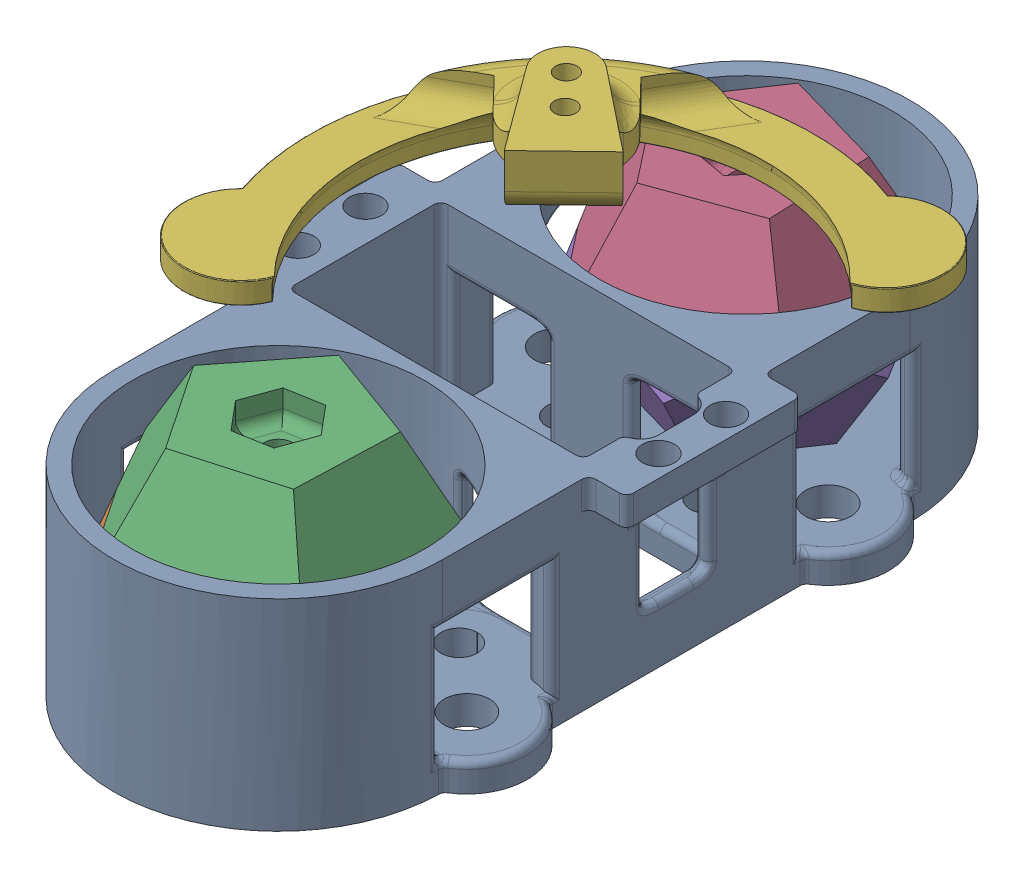
SolidWorks assembly MS25_Marker_DropperAssembly, configuration Default. Lengths in mm.
Overall size (83.01 48 114.65).
6 component instances, 4 part files, 7 mates.
Components (placement in the parent):
- MS25_Marker_DropperBody-1: MS25_Marker_DropperBody [Default] at (-21.4073 8.5238 12.4012) size (56.8 28.3 111.9)
- MS25_Marker_DodecBoltSide-1: MS25_Marker_DodecBoltSide [Default] at (-21.4073 -11.7762 45.2512) x (-0.96134 0 0.275365) z (-0.275365 0 -0.96134) size (36.8 15 36.85)
- MS25_Marker_DodecNutSide-1: MS25_Marker_DodecNutSide [Default] at (-21.4073 18.2238 45.2512) x (0.939596 0 0.342286) z (0.342286 0 -0.939596) size (36.8 15 36.85)
- MS25_Marker_DodecNutSide-2: MS25_Marker_DodecNutSide [Default] at (-21.4073 18.2238 -20.4488) x (-0.939596 0 0.342286) z (0.342286 0 0.939596) size (36.8 15 36.85)
- MS25_Marker_DodecBoltSide-3: MS25_Marker_DodecBoltSide [Default] at (-21.4073 -11.7762 -20.4488) x (0.96134 0 0.275365) z (-0.275365 0 0.96134) size (36.8 15 36.85)
- MS25_Marker_D646WPHornAdapter-1: MS25_Marker_D646WPHornAdapter [Default] at (-14.3573 22.2238 12.4012) x (-0.720754 0 0.693191) z (0.693191 0 0.720754) size (80.17 13.01 36.4)
Mates (geometry in assembly coordinates):
- Coincident1: coincident anti-aligned: plane of MS25_Marker_DropperBody-1 through (-21.4073 -11.7762 12.4012) normal (0 1 0); plane of MS25_Marker_DodecNutHalf-1 through (-21.4073 -11.7762 45.2512) normal (0 -1 0)
- Coincident5: coincident anti-aligned: plane of MS25_Marker_DodecNutHalf-1 through (-21.4073 3.2238 45.2512) normal (0 1 0); plane of MS25_Marker_DodecBoltHalf-1 through (-21.4073 3.2238 45.2512) normal (0 -1 0)
- Coincident8: coincident aligned: line of MS25_Marker_DodecNutHalf-1 through (-38.6965 3.2238 38.9529) axis (-0.035182 0 0.999381); line of MS25_Marker_DodecBoltHalf-1 through (-38.6965 3.2238 38.9529) axis (-0.035182 0 0.999381)
- Coincident9: coincident: point of MS25_Marker_DodecNutHalf-1; point of MS25_Marker_DodecBoltHalf-1
- Concentric1: concentric anti-aligned: circle of MS25_Marker_DropperBody-1; circle of MS25_Marker_D956WPHornAdapter-1
- Coincident11: coincident aligned: circle of MS25_Marker_DropperBody-1; plane of MS25_Marker_D956WPHornAdapter-1 through (-14.3573 32.2238 12.4012) normal (0 1 0)
- Concentric2: concentric anti-aligned: circle of MS25_Marker_DropperBody-1; cylinder of MS25_Marker_DodecNutSide-2 through (-21.4073 -8.0899 -20.4488) axis (0 1 0) radius 2
